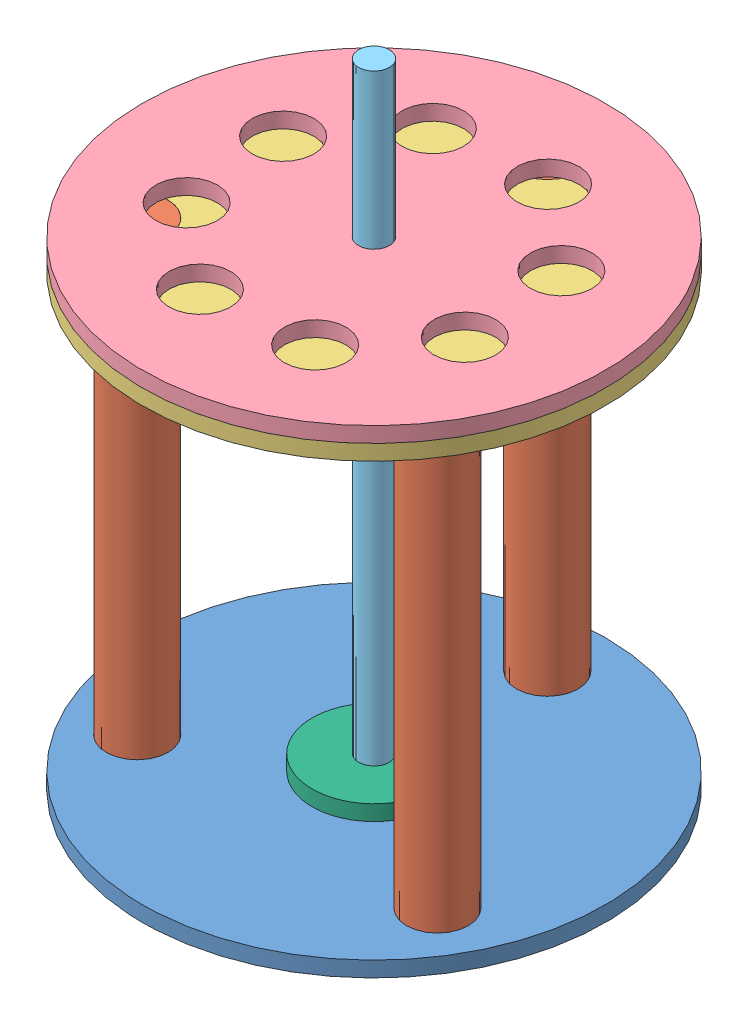
SolidWorks assembly wire_assembly, configuration Default. Lengths in mm.
Overall size (204.9 205 204.9).
8 component instances, 6 part files, 15 mates.
Components (placement in the parent):
- base-1: base [Default] at (64.6773 66.8347 103.4393) size (150 5 150)
- support-1: support [Default] at (16.034 66.8347 131.5235) x (0.995502 0 -0.094738) z (0.094738 0 0.995502) size (20 150 20)
- support-2: support [Default] at (64.6773 66.8347 47.2707) size (20 150 20)
- support-3: support [Default] at (113.3207 66.8347 131.5235) size (20 150 20)
- top-1: top [Default] at (64.6773 216.8347 103.4393) x (0.5 0 -0.866025) z (-0.866025 0 -0.5) size (150 5 150)
- compass holder-1: compass holder [Default] at (64.6773 216.8347 103.4393) x (-0.46276 0 -0.886484) z (0.886484 0 -0.46276) size (150 5 150)
- copper wire-1: copper wire [Default] at (64.6773 71.8347 103.4393) x (0.770936 0 0.636912) z (-0.636912 0 0.770936) size (10 200 10)
- holding washer-1: holding washer [Default] at (64.6773 71.8347 103.4393) x (-0.910159 0 -0.41426) z (0.41426 0 -0.910159) size (40 5 40)
Mates (geometry in assembly coordinates):
- Concentric1: concentric anti-aligned: cylinder of base-1 through (16.034 66.8347 131.5235) axis (0 1 0) radius 10; cylinder of support-1 through (16.034 216.8347 131.5235) axis (0 -1 0) radius 10
- Coincident1: coincident aligned: circle of base-1; circle of support-1
- Concentric2: concentric anti-aligned: cylinder of base-1 through (113.3207 66.8347 131.5235) axis (0 1 0) radius 10; cylinder of support-3 through (113.3207 216.8347 131.5235) axis (0 -1 0) radius 10
- Coincident2: coincident aligned: circle of base-1; circle of support-3
- Concentric3: concentric anti-aligned: cylinder of base-1 through (64.6773 66.8347 47.2707) axis (0 1 0) radius 10; cylinder of support-2 through (64.6773 216.8347 47.2707) axis (0 -1 0) radius 10
- Coincident3: coincident aligned: circle of base-1; circle of support-2
- Concentric7: concentric aligned: cylinder of support-1 through (16.034 216.8347 131.5235) axis (0 -1 0) radius 10; cylinder of top-1 through (16.034 216.8347 131.5235) axis (0 -1 0) radius 10
- Concentric9: concentric aligned: cylinder of support-2 through (64.6773 216.8347 47.2707) axis (0 -1 0) radius 10; cylinder of top-1 through (64.6773 216.8347 47.2707) axis (0 -1 0) radius 10
- Coincident8: coincident anti-aligned: plane of top-1 through (64.6773 216.8347 103.4393) normal (0 1 0); plane of compass holder-1 through (64.6773 216.8347 103.4393) normal (0 -1 0)
- Coincident9: coincident anti-aligned: circle of top-1; circle of compass holder-1
- Concentric10: concentric anti-aligned: cylinder of compass holder-1 through (64.6773 216.8347 103.4393) axis (0 1 0) radius 5; cylinder of copper wire-1 through (64.6773 271.8347 103.4393) axis (0 -1 0) radius 5
- Coincident10: coincident anti-aligned: plane of base-1 through (64.6773 71.8347 103.4393) normal (0 1 0); plane of copper wire-1 through (64.6773 71.8347 103.4393) normal (0 -1 0)
- Concentric11: concentric aligned: cylinder of copper wire-1 through (64.6773 271.8347 103.4393) axis (0 -1 0) radius 5; cylinder of holding washer-1 through (64.6773 76.8347 103.4393) axis (0 -1 0) radius 5
- Coincident11: coincident anti-aligned: plane of base-1 through (64.6773 71.8347 103.4393) normal (0 1 0); plane of holding washer-1 through (64.6773 71.8347 103.4393) normal (0 -1 0)
- Coincident12: coincident anti-aligned: plane of support-3 through (113.3207 216.8347 131.5235) normal (0 1 0); plane of compass holder-1 through (64.6773 216.8347 103.4393) normal (0 -1 0)
